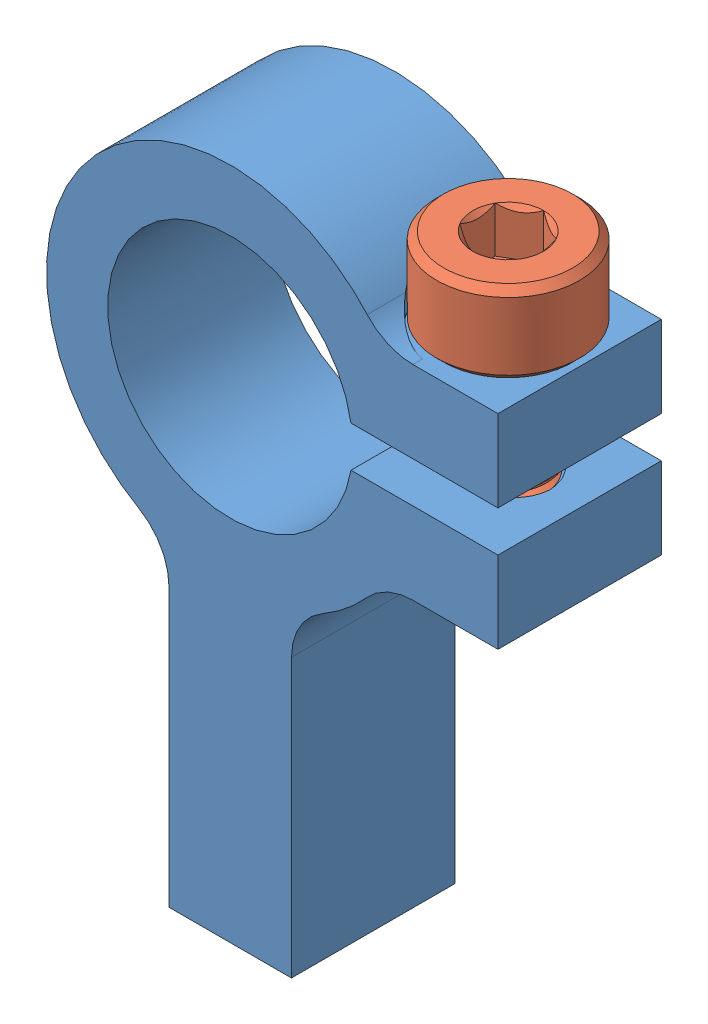
SolidWorks assembly 1-Side, 1-Post Clamping Mount (12mm Bore) 1403-0024-0012, configuration Default. Lengths in mm.
Overall size (22.12 33.01 8).
2 component instances, 2 part files, 0 mates.
Components (placement in the parent):
- 1403-0024-0012 without hardware.step-1: 1403-0024-0012 without hardware.step [Default] at (1.6589 6.6635 -0.7486) size (22.12 33 8)
- 2800-0004-0010.step-1: 2800-0004-0010.step [Default] at (11.275 1.6635 3.2514) size (7 14.01 7)
